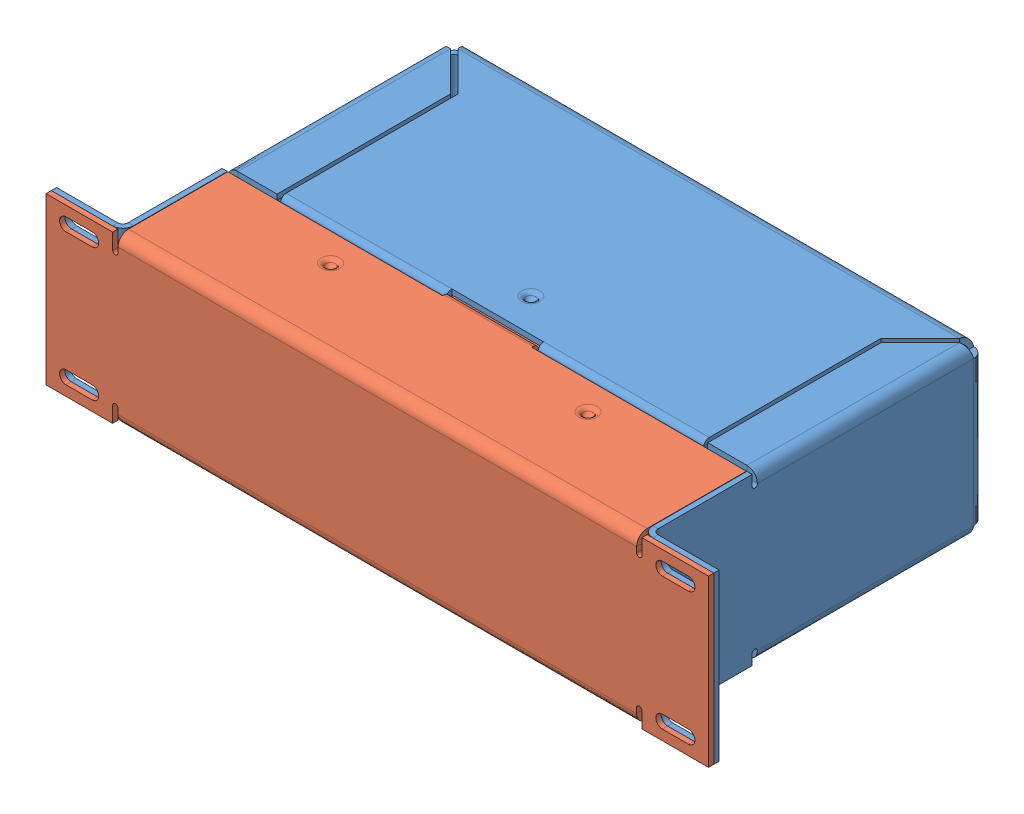
SolidWorks assembly FMA-15-02-KIT, configuration 8x5x2.5. Lengths in mm.
Overall size (254 63.5 131.06).
2 component instances, 2 part files, 4 mates.
Components (placement in the parent):
- FMA-15-02-CHASSIS^FMA-15-02-KIT-1: FMA-15-02-CHASSIS^FMA-15-02-KIT [8x5x2.5] at origin size (254 63.5 129.03) (virtual)
- FMA-15-02-FRONT^FMA-15-02-KIT-1: FMA-15-02-FRONT^FMA-15-02-KIT [8x5x2.5] at (0 0 129.032) size (254 63.5 63.95) (virtual)
Mates (geometry in assembly coordinates):
- InPlace1: in place: plane of FMA-15-02-CHASSIS^FMA-15-02-KIT-1 through (-127 38.1 103.632) normal (0 0 1); plane of ? through (0 0 103.632) normal (0 0 1); moOrthogonalPlaneRef_w of FMA-15-02-CHASSIS^FMA-15-02-KIT-1 through (-127 38.1 103.632) normal (0 0 1); plane of ? through (0 0 103.632) normal (0 1 0); plane of FMA-15-02-CHASSIS^FMA-15-02-KIT-1 through (-127 38.1 103.632) normal (0 0 1); plane of ? through (0 0 103.632) normal (1 0 0); plane of FMA-15-02-CHASSIS^FMA-15-02-KIT-1 through (-101.6 31.75 129.032) normal (0 0 1); unknown of FMA-15-02-FRONT^FMA-15-02-KIT-1
- Coincident1: coincident aligned: plane of FMA-15-02-CHASSIS^FMA-15-02-KIT-1; plane of FMA-15-02-FRONT^FMA-15-02-KIT-1
- Coincident2: coincident aligned: moOrthogonalPlaneRef_w of FMA-15-02-CHASSIS^FMA-15-02-KIT-1 through (0 0 129.032) normal (0 1 0); plane of FMA-15-02-FRONT^FMA-15-02-KIT-1 through (0 0 129.032) normal (0 1 0)
- Coincident3: coincident anti-aligned: moOrthogonalPlaneRef_w of FMA-15-02-CHASSIS^FMA-15-02-KIT-1 through (0 0 129.032) normal (-1 0 0); plane of FMA-15-02-FRONT^FMA-15-02-KIT-1 through (0 0 129.032) normal (1 0 0)
